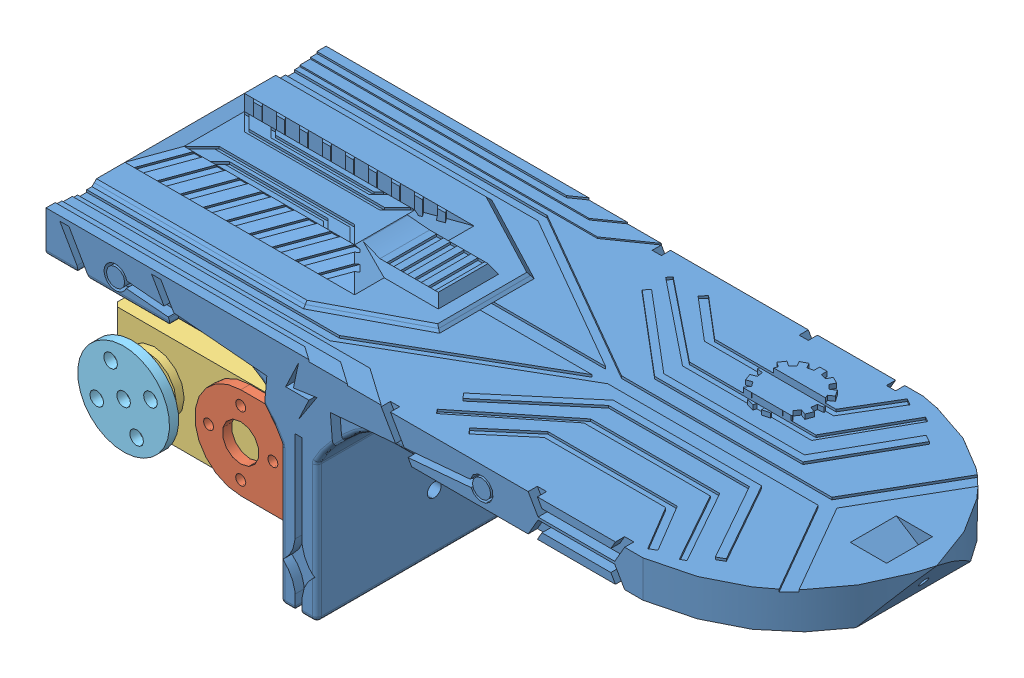
SolidWorks assembly leg3, configuration Default. Lengths in mm.
Overall size (166.83 65.98 61.18).
6 component instances, 5 part files, 3 mates.
Components (placement in the parent):
- leg1-3-1: leg1-3 [Default] at (23.9761 103.7424 136.4642) size (166.48 52 61.18)
- servo_asm-1: servo_asm [默认] at (568.5443 -143.7853 416.803) x (-1 0 0) z (0 0 -1) size (51.36 26.71 52.4)
  - ZJ-DUAN-1: ZJ-DUAN [默认] at (575.5682 225.0277 280.3388) x (-1 0 0) z (0 -1 0) size (27 44.2 20)
  - 舵机-1: 舵机 [默认] at (546.9248 215.0277 274.2891) x (-1 0 0) z (0 0 -1) size (40 20 48.7)
  - 无齿盘-1: 无齿盘 [默认] at (596.5682 225.0277 306.1388) x (-0.041997 -0.999118 0) z (0.999118 -0.041997 0) size (20 3 20)
  - 有齿盘-1: 有齿盘 [默认] at (596.5682 225.0277 253.7388) x (0.900229 -0.435417 0) z (-0.435417 -0.900229 0) size (20 4.2 20)
Mates (geometry in assembly coordinates):
- 重合1: coincident anti-aligned: plane of leg1-3-1 through (9.9761 103.7424 136.4642) normal (-1 0 0); plane of servo_asm-1/ZJ-DUAN-1 through (9.9761 91.2424 114.3642) normal (1 0 0)
- 同心1: concentric anti-aligned: cylinder of leg1-3-1 through (36.9761 81.2424 136.4642) axis (-1 0 0) radius 3; cylinder of servo_asm-1/ZJ-DUAN-1 through (9.9761 81.2424 136.4642) axis (1 0 0) radius 3
- 平行1: parallel aligned: plane of leg1-3-1 through (110.5817 111.7424 157.2548) normal (0 1 0); plane of servo_asm-1/舵机-1 through (21.6195 91.2424 142.5139) normal (0 1 0)
